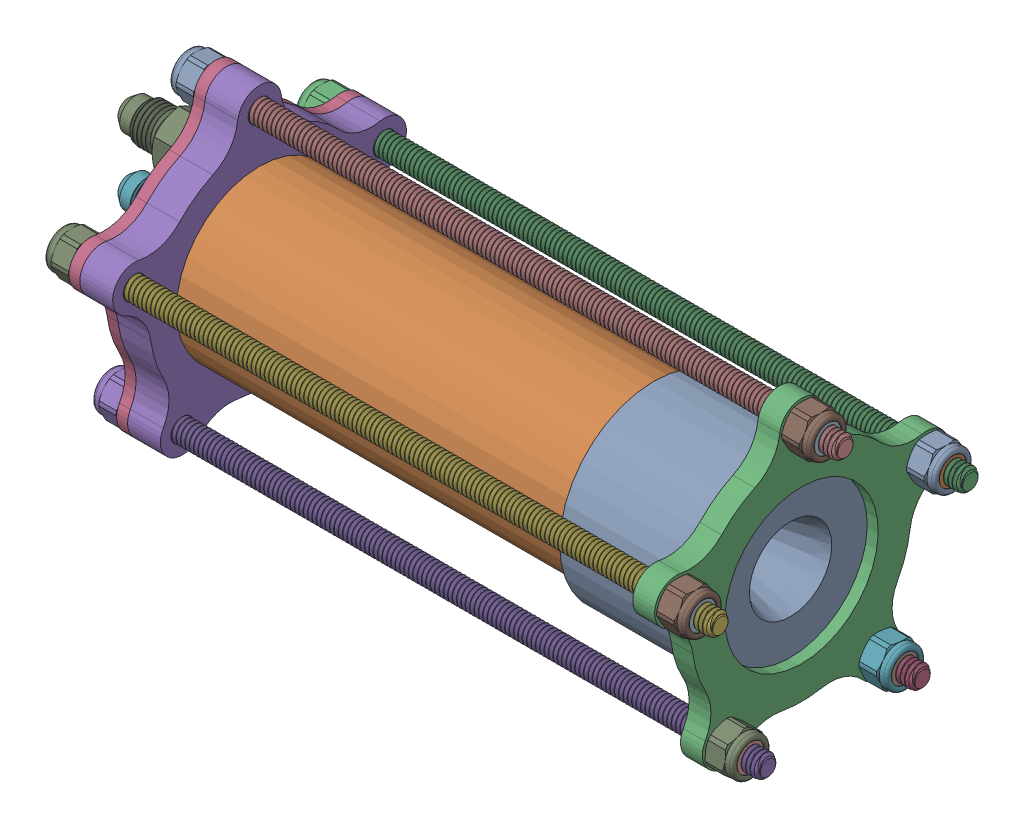
SolidWorks assembly Simple Vulcan Assembly, configuration Default. Lengths in mm.
Overall size (208.43 106.23 103.95).
21 component instances, 7 part files, 43 mates.
Components (placement in the parent):
- Copper Nozzle-1: Copper Nozzle [Default] at origin size (39.65 54.61 54.61)
- Tube Chamber-1: Tube Chamber [Default] at (-117.475 0 0) x (1 0 0) z (0 -0.009858 0.999951) size (120.65 48.26 48.26)
- Nozzle Retainer-1: Nozzle Retainer [Default] at (42.8257 0 0) x (0 0.951057 0.309017) z (0 -0.309017 0.951057) size (85.17 6.35 81.62)
- Alternate Injector-1: Alternate Injector [Default] at (-117.475 0 0) x (0 1 0) z (0 0 1) size (81.62 15.88 85.17)
- 50715K831_37 Degree Flared Fitting for Stainless Steel Tubing-1: 50715K831_37 Degree Flared Fitting for Stainless Steel Tubing [50715K831] at (-136.652 0 0) x (0 0.441413 0.897304) z (-1 0 0) size (14.29 16.5 31.43)
- 50715K831_37 Degree Flared Fitting for Stainless Steel Tubing-2: 50715K831_37 Degree Flared Fitting for Stainless Steel Tubing [50715K831] at (-136.652 19.304 0) x (0 -0.001712 0.999999) z (-1 0 0) size (14.29 16.5 31.43)
- 92580A327_Grade B7 Medium-Strength Steel Threaded Rod-1: 92580A327_Grade B7 Medium-Strength Steel Threaded Rod [92580A327] at (-33.3743 38.1 0) x (0 -0.548106 -0.836409) z (1 0 0) size (7.33 6.43 179.17)
- 95615A120_Medium-Strength Steel Nylon-Insert Locknut-1: 95615A120_Medium-Strength Steel Nylon-Insert Locknut [95615A120] at (46.8008 38.1 0) x (0 -1 0) z (0 0 1) size (11.15 7.95 12.24)
- 95615A120_Medium-Strength Steel Nylon-Insert Locknut-2: 95615A120_Medium-Strength Steel Nylon-Insert Locknut [95615A120] at (-130.9751 38.1 0) x (0 0.994675 -0.10306) z (0 0.10306 0.994675) size (11.15 7.95 12.24)
- 92580A327_Grade B7 Medium-Strength Steel Threaded Rod-3: 92580A327_Grade B7 Medium-Strength Steel Threaded Rod [92580A327] at (-33.3743 11.7735 -36.2353) x (0 -0.548106 -0.836409) z (1 0 0) size (7.33 6.43 179.17)
- 92580A327_Grade B7 Medium-Strength Steel Threaded Rod-4: 92580A327_Grade B7 Medium-Strength Steel Threaded Rod [92580A327] at (-33.3743 -30.8235 -22.3946) x (0 -0.548106 -0.836409) z (1 0 0) size (7.33 6.43 179.17)
- 92580A327_Grade B7 Medium-Strength Steel Threaded Rod-5: 92580A327_Grade B7 Medium-Strength Steel Threaded Rod [92580A327] at (-33.3743 -30.8235 22.3946) x (0 -0.548106 -0.836409) z (1 0 0) size (7.33 6.43 179.17)
- 92580A327_Grade B7 Medium-Strength Steel Threaded Rod-6: 92580A327_Grade B7 Medium-Strength Steel Threaded Rod [92580A327] at (-33.3743 11.7735 36.2353) x (0 -0.64897 -0.760814) z (1 0 0) size (7.33 6.43 179.17)
- 95615A120_Medium-Strength Steel Nylon-Insert Locknut-5: 95615A120_Medium-Strength Steel Nylon-Insert Locknut [95615A120] at (46.8008 -30.8235 -22.3946) x (0 -0.994924 0.100626) z (0 0.100626 0.994924) size (11.15 7.95 12.24)
- 95615A120_Medium-Strength Steel Nylon-Insert Locknut-6: 95615A120_Medium-Strength Steel Nylon-Insert Locknut [95615A120] at (46.8008 -30.8235 22.3946) x (0 -0.935838 -0.352431) z (0 -0.352431 0.935838) size (11.15 7.95 12.24)
- 95615A120_Medium-Strength Steel Nylon-Insert Locknut-7: 95615A120_Medium-Strength Steel Nylon-Insert Locknut [95615A120] at (46.8008 11.7735 36.2353) x (0 -1 0) z (0 0 1) size (11.15 7.95 12.24)
- 95615A120_Medium-Strength Steel Nylon-Insert Locknut-8: 95615A120_Medium-Strength Steel Nylon-Insert Locknut [95615A120] at (46.8008 11.7735 -36.2353) x (0 -1 0) z (0 0 1) size (11.15 7.95 12.24)
- 95615A120_Medium-Strength Steel Nylon-Insert Locknut-9: 95615A120_Medium-Strength Steel Nylon-Insert Locknut [95615A120] at (-130.9751 11.7735 -36.2353) x (0 1 0) z (0 0 1) size (11.15 7.95 12.24)
- 95615A120_Medium-Strength Steel Nylon-Insert Locknut-10: 95615A120_Medium-Strength Steel Nylon-Insert Locknut [95615A120] at (-130.9751 -30.8235 22.3946) x (0 0.994828 -0.101578) z (0 0.101578 0.994828) size (11.15 7.95 12.24)
- 95615A120_Medium-Strength Steel Nylon-Insert Locknut-11: 95615A120_Medium-Strength Steel Nylon-Insert Locknut [95615A120] at (-130.9751 -30.8235 -22.3946) x (0 1 0) z (0 0 1) size (11.15 7.95 12.24)
- 95615A120_Medium-Strength Steel Nylon-Insert Locknut-12: 95615A120_Medium-Strength Steel Nylon-Insert Locknut [95615A120] at (-130.9751 11.7735 36.2353) x (0 1 0) z (0 0 1) size (11.15 7.95 12.24)
Mates (geometry in assembly coordinates):
- Concentric1: concentric aligned: cylinder of Copper Nozzle-1 through (0 0 0) axis (-1 0 0) radius 24.13; cylinder of Tube Chamber-1 through (3.175 0 0) axis (-1 0 0) radius 24.13
- Coincident1: coincident anti-aligned: plane of Copper Nozzle-1 through (3.175 24.13 0) normal (-1 0 0); plane of Tube Chamber-1 through (3.175 0 0) normal (1 0 0)
- Coincident3: coincident anti-aligned: plane of Copper Nozzle-1 through (39.6507 11.938 0) normal (1 0 0); plane of Nozzle Retainer-1 through (39.6507 0 0) normal (-1 0 0)
- Concentric3: concentric anti-aligned: cylinder of Copper Nozzle-1 through (0 0 0) axis (-1 0 0) radius 27.305; cylinder of Nozzle Retainer-1 through (36.4757 0 0) axis (1 0 0) radius 27.305
- Parallel1: parallel aligned: cylinder of Nozzle Retainer-1 through (36.4757 38.1 0) axis (1 0 0) radius 3.175; cylinder of Alternate Injector-1 through (-145.9827 38.1 0) axis (1 0 0) radius 3.302
- Coincident5: coincident anti-aligned: plane of Tube Chamber-1 through (-117.475 0 0) normal (-1 0 0); plane of Alternate Injector-1 through (-117.475 0 0) normal (1 0 0)
- Concentric7: concentric anti-aligned: cylinder of Nozzle Retainer-1 through (36.4757 38.1 0) axis (1 0 0) radius 3.175; cylinder of Alternate Injector-1 through (-123.825 38.1 0) axis (-1 0 0) radius 3.302
- Concentric8: concentric aligned: cylinder of Tube Chamber-1 through (3.175 0 0) axis (-1 0 0) radius 24.13; cylinder of Alternate Injector-1 through (-120.65 0 0) axis (-1 0 0) radius 24.13
- Concentric9: concentric anti-aligned: cylinder of Alternate Injector-1 through (-120.65 0 0) axis (-1 0 0) radius 5.5563; cylinder of 50715K831_37 Degree Flared Fitting for Stainless Steel Tubing-1 through (-121.031 0 0) axis (1 0 0) radius 4.6037
- Concentric10: concentric aligned: cylinder of 50715K831_37 Degree Flared Fitting for Stainless Steel Tubing-2 through (-121.031 19.304 0) axis (1 0 0) radius 4.6037; cylinder of Alternate Injector-1 through (-130.175 19.304 0) axis (1 0 0) radius 5.5563
- Coincident8: coincident anti-aligned: plane of Alternate Injector-1 through (-130.175 19.304 0) normal (-1 0 0); plane of 50715K831_37 Degree Flared Fitting for Stainless Steel Tubing-2 through (-130.175 19.304 0) normal (1 0 0)
- Coincident9: coincident anti-aligned: plane of Alternate Injector-1 through (-130.175 19.304 0) normal (-1 0 0); plane of 50715K831_37 Degree Flared Fitting for Stainless Steel Tubing-1 through (-130.175 0 0) normal (1 0 0)
- Parallel2: parallel aligned: plane of Alternate Injector-1 through (-130.175 19.304 10.3187) normal (0 0 1)
- Concentric11: concentric anti-aligned: cylinder of Alternate Injector-1 through (-123.825 38.1 0) axis (-1 0 0) radius 3.302; line of 92580A327_Grade B7 Medium-Strength Steel Threaded Rod-1 through (-121.3218 38.1 0) axis (1 0 0)
- Concentric12: concentric anti-aligned: cylinder of Nozzle Retainer-1 through (36.4757 38.1 0) axis (1 0 0) radius 6.35; cylinder of 95615A120_Medium-Strength Steel Nylon-Insert Locknut-1 through (42.8257 38.1 0) axis (-1 0 0) radius 2.3501
- Coincident10: coincident anti-aligned: plane of Nozzle Retainer-1 through (42.8257 0 0) normal (1 0 0); plane of 95615A120_Medium-Strength Steel Nylon-Insert Locknut-1 through (42.8257 38.1 0) normal (-1 0 0)
- Concentric13: concentric anti-aligned: cylinder of Alternate Injector-1 through (-123.825 38.1 0) axis (-1 0 0) radius 6.35; cylinder of 95615A120_Medium-Strength Steel Nylon-Insert Locknut-2 through (-127 38.1 0) axis (1 0 0) radius 2.3501
- Coincident11: coincident anti-aligned: plane of Alternate Injector-1 through (-127 0 0) normal (-1 0 0); plane of 95615A120_Medium-Strength Steel Nylon-Insert Locknut-2 through (-127 38.1 0) normal (1 0 0)
- Concentric14: concentric aligned: cylinder of Nozzle Retainer-1 through (36.4757 11.7735 -36.2353) axis (1 0 0) radius 3.175; line of 92580A327_Grade B7 Medium-Strength Steel Threaded Rod-3 through (-121.3218 11.7735 -36.2353) axis (1 0 0)
- Concentric15: concentric aligned: cylinder of Nozzle Retainer-1 through (36.4757 -30.8235 -22.3946) axis (1 0 0) radius 3.175; line of 92580A327_Grade B7 Medium-Strength Steel Threaded Rod-4 through (-121.3218 -30.8235 -22.3946) axis (1 0 0)
- Concentric16: concentric aligned: cylinder of Nozzle Retainer-1 through (36.4757 -30.8235 22.3946) axis (1 0 0) radius 3.175; line of 92580A327_Grade B7 Medium-Strength Steel Threaded Rod-5 through (-121.3218 -30.8235 22.3946) axis (1 0 0)
- Concentric17: concentric aligned: cylinder of Nozzle Retainer-1 through (36.4757 11.7735 36.2353) axis (1 0 0) radius 3.175; line of 92580A327_Grade B7 Medium-Strength Steel Threaded Rod-6 through (-121.3218 11.7735 36.2353) axis (1 0 0)
- Coincident12: coincident aligned: plane of 92580A327_Grade B7 Medium-Strength Steel Threaded Rod-1 through (55.5257 38.1 0) normal (1 0 0); plane of 92580A327_Grade B7 Medium-Strength Steel Threaded Rod-6 through (55.5257 11.7735 36.2353) normal (1 0 0)
- Coincident13: coincident aligned: plane of 92580A327_Grade B7 Medium-Strength Steel Threaded Rod-1 through (55.5257 38.1 0) normal (1 0 0); plane of 92580A327_Grade B7 Medium-Strength Steel Threaded Rod-3 through (55.5257 11.7735 -36.2353) normal (1 0 0)
- Coincident14: coincident aligned: plane of 92580A327_Grade B7 Medium-Strength Steel Threaded Rod-3 through (55.5257 11.7735 -36.2353) normal (1 0 0); plane of 92580A327_Grade B7 Medium-Strength Steel Threaded Rod-4 through (55.5257 -30.8235 -22.3946) normal (1 0 0)
- Coincident15: coincident aligned: plane of 92580A327_Grade B7 Medium-Strength Steel Threaded Rod-5 through (55.5257 -30.8235 22.3946) normal (1 0 0); plane of 92580A327_Grade B7 Medium-Strength Steel Threaded Rod-6 through (55.5257 11.7735 36.2353) normal (1 0 0)
- Distance1: distance = 12.7 mm aligned: plane of 92580A327_Grade B7 Medium-Strength Steel Threaded Rod-5 through (55.5257 -30.8235 22.3946) normal (1 0 0); plane of Nozzle Retainer-1 through (42.8257 0 0) normal (1 0 0)
- Concentric18: concentric anti-aligned: cylinder of Nozzle Retainer-1 through (36.4757 11.7735 -36.2353) axis (1 0 0) radius 6.35; cylinder of 95615A120_Medium-Strength Steel Nylon-Insert Locknut-8 through (42.8257 11.7735 -36.2353) axis (-1 0 0) radius 2.3501
- Coincident17: coincident anti-aligned: plane of Nozzle Retainer-1 through (42.8257 0 0) normal (1 0 0); plane of 95615A120_Medium-Strength Steel Nylon-Insert Locknut-8 through (42.8257 11.7735 -36.2353) normal (-1 0 0)
- Concentric19: concentric anti-aligned: cylinder of Nozzle Retainer-1 through (36.4757 -30.8235 -22.3946) axis (1 0 0) radius 6.35; cylinder of 95615A120_Medium-Strength Steel Nylon-Insert Locknut-5 through (42.8257 -30.8235 -22.3946) axis (-1 0 0) radius 2.3501
- Coincident18: coincident anti-aligned: plane of Nozzle Retainer-1 through (42.8257 0 0) normal (1 0 0); plane of 95615A120_Medium-Strength Steel Nylon-Insert Locknut-5 through (42.8257 -30.8235 -22.3946) normal (-1 0 0)
- Concentric20: concentric anti-aligned: cylinder of Nozzle Retainer-1 through (36.4757 -30.8235 22.3946) axis (1 0 0) radius 6.35; cylinder of 95615A120_Medium-Strength Steel Nylon-Insert Locknut-6 through (42.8257 -30.8235 22.3946) axis (-1 0 0) radius 2.3501
- Coincident19: coincident anti-aligned: plane of Nozzle Retainer-1 through (42.8257 0 0) normal (1 0 0); plane of 95615A120_Medium-Strength Steel Nylon-Insert Locknut-6 through (42.8257 -30.8235 22.3946) normal (-1 0 0)
- Concentric21: concentric anti-aligned: cylinder of Nozzle Retainer-1 through (36.4757 11.7735 36.2353) axis (1 0 0) radius 6.35; cylinder of 95615A120_Medium-Strength Steel Nylon-Insert Locknut-7 through (42.8257 11.7735 36.2353) axis (-1 0 0) radius 2.3501
- Coincident20: coincident anti-aligned: plane of Nozzle Retainer-1 through (42.8257 0 0) normal (1 0 0); plane of 95615A120_Medium-Strength Steel Nylon-Insert Locknut-7 through (42.8257 11.7735 36.2353) normal (-1 0 0)
- Concentric22: concentric anti-aligned: cylinder of Alternate Injector-1 through (-123.825 11.7735 36.2353) axis (-1 0 0) radius 6.35; cylinder of 95615A120_Medium-Strength Steel Nylon-Insert Locknut-12 through (-127 11.7735 36.2353) axis (1 0 0) radius 2.3501
- Coincident21: coincident anti-aligned: plane of Alternate Injector-1 through (-127 0 0) normal (-1 0 0); plane of 95615A120_Medium-Strength Steel Nylon-Insert Locknut-12 through (-127 11.7735 36.2353) normal (1 0 0)
- Concentric23: concentric anti-aligned: cylinder of Alternate Injector-1 through (-123.825 11.7735 -36.2353) axis (-1 0 0) radius 6.35; cylinder of 95615A120_Medium-Strength Steel Nylon-Insert Locknut-9 through (-127 11.7735 -36.2353) axis (1 0 0) radius 2.3501
- Coincident22: coincident anti-aligned: plane of Alternate Injector-1 through (-127 0 0) normal (-1 0 0); plane of 95615A120_Medium-Strength Steel Nylon-Insert Locknut-9 through (-127 11.7735 -36.2353) normal (1 0 0)
- Concentric24: concentric anti-aligned: cylinder of Alternate Injector-1 through (-123.825 -30.8235 -22.3946) axis (-1 0 0) radius 6.35; cylinder of 95615A120_Medium-Strength Steel Nylon-Insert Locknut-11 through (-127 -30.8235 -22.3946) axis (1 0 0) radius 2.3501
- Coincident23: coincident anti-aligned: plane of Alternate Injector-1 through (-127 0 0) normal (-1 0 0); plane of 95615A120_Medium-Strength Steel Nylon-Insert Locknut-11 through (-127 -30.8235 -22.3946) normal (1 0 0)
- Concentric25: concentric anti-aligned: cylinder of Alternate Injector-1 through (-123.825 -30.8235 22.3946) axis (-1 0 0) radius 6.35; cylinder of 95615A120_Medium-Strength Steel Nylon-Insert Locknut-10 through (-127 -30.8235 22.3946) axis (1 0 0) radius 2.3501
- Coincident24: coincident anti-aligned: plane of Alternate Injector-1 through (-127 0 0) normal (-1 0 0); plane of 95615A120_Medium-Strength Steel Nylon-Insert Locknut-10 through (-127 -30.8235 22.3946) normal (1 0 0)
